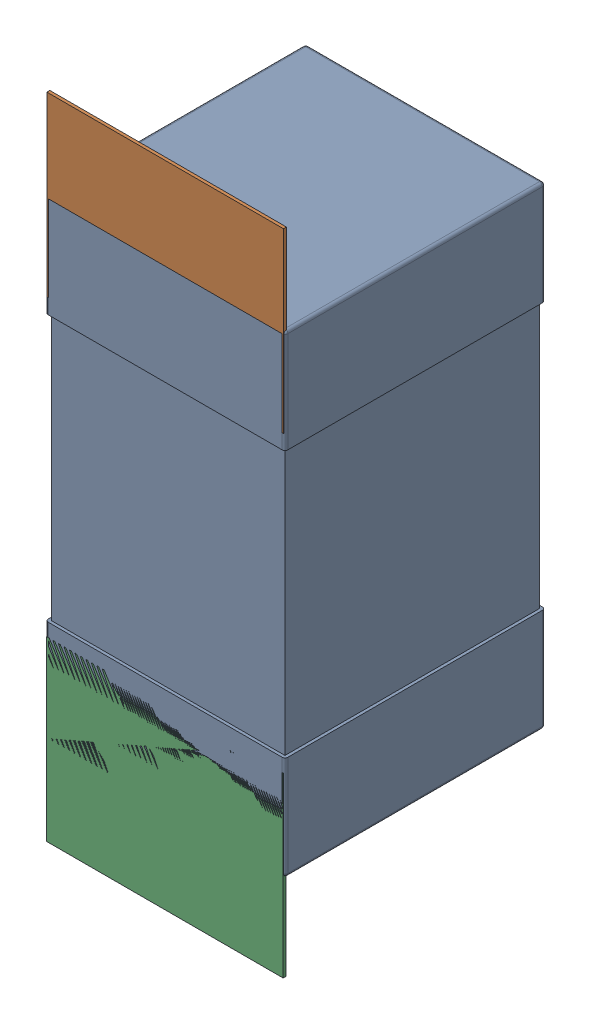
SolidWorks assembly C76, configuration Défaut. Lengths in mm.
Overall size (0.81 2.19 0.88).
5 component instances, 2 part files, 0 mates.
Components (placement in the parent):
- 0603_C-1: 0603_C [Défaut] at (18.3896 -9.3782 -2.0818) x (0 1 0) z (0 0 -1) size (1.6 0.81 0.88)
- 8260087904-1: 8260087904 [Défaut] at (18.3896 -8.1282 -2.0918) size (0.8 0.6 0.01)
  - Extruded_1211-1: Extruded_1211 [Défaut] at origin size (0.8 0.6 0.01)
- 8260087904-2: 8260087904 [Défaut] at (18.3883 -9.7231 -2.0918) size (0.8 0.6 0.01)
  - Extruded_1211-1: Extruded_1211 [Défaut] at origin size (0.8 0.6 0.01)
